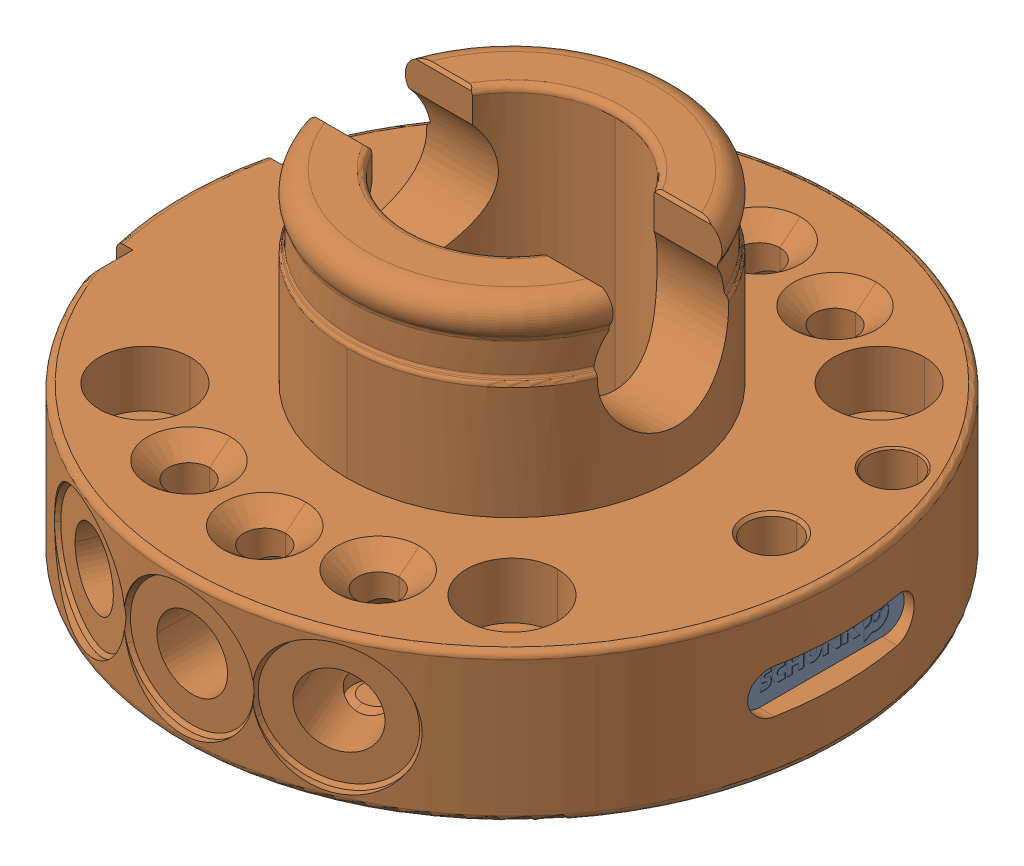
SolidWorks assembly SCHUNK_0310421_SHA_063_000_000_0000ohne, configuration Default. Lengths in mm.
Overall size (80 40.89 80.02).
2 component instances, 2 part files, 0 mates.
Components (placement in the parent):
- SCHUNK_0310421_SHA_063_000_000_0000ohne_3-1: SCHUNK_0310421_SHA_063_000_000_0000ohne_3 [Default] at (37.3 -9 0) x (0 0 -1) z (1 0 0) size (20 5 0.3)
- SCHUNK_0310421_SHA_063_000_000_0000ohne_5-1: SCHUNK_0310421_SHA_063_000_000_0000ohne_5 [Default] at origin size (80 40.89 80.02)
